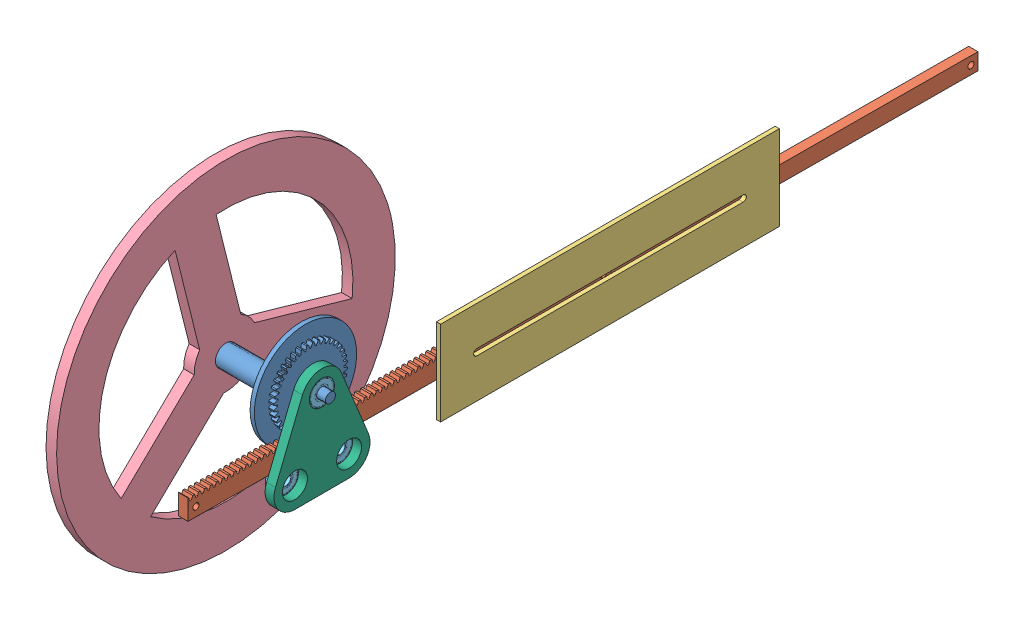
SolidWorks assembly ProgressiveSteering, configuration Default. Lengths in mm.
Overall size (72.15 278.29 519.17).
8 component instances, 6 part files, 18 mates.
Components (placement in the parent):
- SI_sdpsi_s1268z-024s040-2: SI_sdpsi_s1268z-024s040 [Default] at (1.5875 12.3216 3.0771) x (1 0 0) z (0 -0.242292 0.970203) size (65.8 61.38 61.38)
- SI_sdpsi_s1811y-rc-1a-1: SI_sdpsi_s1811y-rc-1a [Default] at (1.5875 -14.4953 -48.953) x (0 0.006403 0.999979) z (-1 0 0) size (474 12.19 5.85)
- slot-1: slot [Default] at (116.0145 -19.3663 -200.266) x (0 0 1) z (-1 0 0) size (203.2 50.8 2.54)
- steering wheel-1: steering wheel [Default] at (-57.15 0 0) x (0 0.242292 -0.970203) z (1 0 0) size (203.2 236.09 6.35)
- 4668K121_Permanently Lubricated Stainless Steel Ball Bearing-1: 4668K121_Permanently Lubricated Stainless Steel Ball Bearing [4668K121] at (7.34 12.3216 3.0771) x (0 0 1) z (-1 0 0) size (15 15 5)
- Part1^ProgressiveSteering-1: Part1^ProgressiveSteering [Default] at (4.5085 -14.0928 -43.074) x (0 0.001491 -0.999999) z (1 0 0) size (57.65 65.11 5.33) (virtual)
- 4668K121_Permanently Lubricated Stainless Steel Ball Bearing-2: 4668K121_Permanently Lubricated Stainless Steel Ball Bearing [4668K121] at (2.0085 -27.6063 -13.2271) x (0 0 -1) z (1 0 0) size (15 15 5)
- 4668K121_Permanently Lubricated Stainless Steel Ball Bearing-3: 4668K121_Permanently Lubricated Stainless Steel Ball Bearing [4668K121] at (2.0085 -27.6547 19.2622) x (0 -0.525584 -0.850741) z (1 0 0) size (15 15 5)
Mates (geometry in assembly coordinates):
- Coincident6: coincident: circle of assembly; circle of SI_sdpsi_s1268z-024s040-2; plane of assembly
- Coincident8: coincident: point of SI_sdpsi_s1268z-024s040-2; point of assembly
- Coincident13: coincident anti-aligned: plane of SI_sdpsi_s1268z-024s040-2 through (1.5875 12.3216 3.0771) normal (1 0 0); plane of SI_sdpsi_s1811y-rc-1a-1 through (1.5875 -14.4953 -48.953) normal (-1 0 0)
- Distance1: distance = 21.082 mm: line of assembly; point of SI_sdpsi_s1268z-024s040-2; line of SI_sdpsi_s1811y-rc-1a-1 through (1.5875 -8.2061 80.3601) axis (0 -0.006403 -0.999979)
- RackPinionMate2: rack pinion = 45.212 mm: line of SI_sdpsi_s1811y-rc-1a-1 through (-1.3335 -21.2766 -175.7852) axis (0 0.006403 0.999979); cylinder of SI_sdpsi_s1268z-024s040-2 through (0 12.3216 3.0771) axis (1 0 0) radius 22.225
- Tangent1: tangent anti-aligned: cylinder of SI_sdpsi_s1811y-rc-1a-1 through (-1.3335 -15.8369 -171.1971) axis (-1 0 0) radius 1.8669; plane of slot-1 through (7.0485 -13.97 -252.431) normal (0 -1 0)
- Concentric6: concentric anti-aligned: cylinder of SI_sdpsi_s1268z-024s040-2 through (-50.8 0 0) axis (1 0 0) radius 6.35; cylinder of steering wheel-1 through (-50.8 0 0) axis (-1 0 0) radius 19.05
- Coincident21: coincident anti-aligned: plane of SI_sdpsi_s1268z-024s040-2 through (-50.8 0 0) normal (-1 0 0); plane of steering wheel-1 through (-50.8 0 0) normal (1 0 0)
- Coincident22: coincident: line of SI_sdpsi_s1268z-024s040-2 through (0 33.6277 8.3979) axis (0 -0.970203 -0.242292); plane of steering wheel-1 through (-57.15 0 0) normal (0 0.242292 -0.970203)
- Distance6: distance = 9.525 mm aligned: plane of slot-1 through (7.0485 9.525 -274.1233) normal (0 1 0)
- Concentric7: concentric anti-aligned: cylinder of SI_sdpsi_s1268z-024s040-2 through (4.84 12.3216 3.0771) axis (1 0 0) radius 3; cylinder of 4668K121_Permanently Lubricated Stainless Steel Ball Bearing-1 through (4.84 12.3216 3.0771) axis (-1 0 0) radius 3
- Coincident24: coincident anti-aligned: plane of SI_sdpsi_s1268z-024s040-2 through (4.84 12.3216 3.0771) normal (1 0 0); plane of 4668K121_Permanently Lubricated Stainless Steel Ball Bearing-1 through (4.84 8.1966 3.0771) normal (-1 0 0)
- Concentric8: concentric anti-aligned: cylinder of Part1^ProgressiveSteering-1 through (96.8058 -27.6547 19.2622) axis (-1 0 0) radius 7.5; cylinder of 4668K121_Permanently Lubricated Stainless Steel Ball Bearing-3 through (4.5085 -27.6547 19.2622) axis (1 0 0) radius 7.5
- Coincident29: coincident anti-aligned: plane of Part1^ProgressiveSteering-1 through (4.5085 12.3216 3.0771) normal (-1 0 0); plane of 4668K121_Permanently Lubricated Stainless Steel Ball Bearing-3 through (4.5085 -31.164 21.4302) normal (1 0 0)
- Concentric9: concentric anti-aligned: cylinder of Part1^ProgressiveSteering-1 through (96.8058 -27.6063 -13.2271) axis (-1 0 0) radius 7.5; cylinder of 4668K121_Permanently Lubricated Stainless Steel Ball Bearing-2 through (4.5085 -27.6063 -13.2271) axis (1 0 0) radius 7.5
- Coincident30: coincident anti-aligned: plane of Part1^ProgressiveSteering-1 through (4.5085 12.3216 3.0771) normal (-1 0 0); plane of 4668K121_Permanently Lubricated Stainless Steel Ball Bearing-2 through (4.5085 -31.7313 -13.2271) normal (1 0 0)
- Concentric10: concentric aligned: circle of 4668K121_Permanently Lubricated Stainless Steel Ball Bearing-1; circle of Part1^ProgressiveSteering-1
- Tangent2: tangent anti-aligned: plane of SI_sdpsi_s1811y-rc-1a-1 through (4.5085 -21.4044 -175.9113) normal (0 -0.999979 0.006403); cylinder of 4668K121_Permanently Lubricated Stainless Steel Ball Bearing-3 through (4.5085 -27.6547 19.2622) axis (1 0 0) radius 7.5
